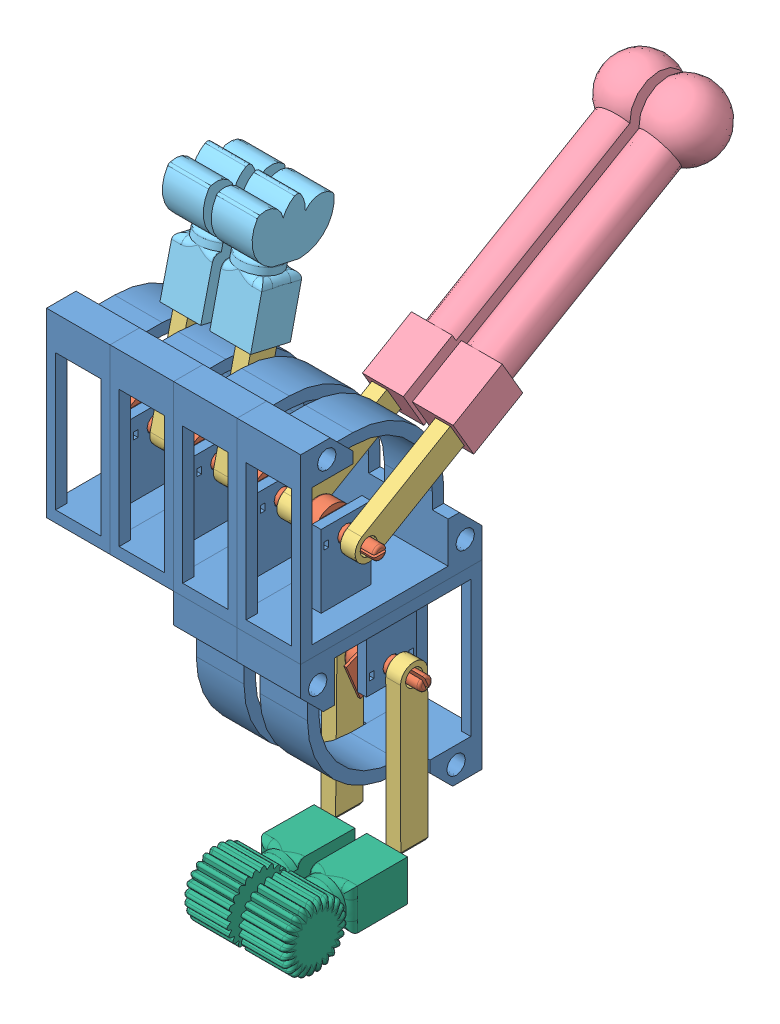
SolidWorks assembly throttle_quadrant_module_v3, configuration По умолчанию. Lengths in mm.
Overall size (120 253.77 210.33).
24 component instances, 6 part files, 57 mates.
Components (placement in the parent):
- throttle_quadrant_axis_module_throttle_quadrant01a-1: throttle_quadrant_axis_module_throttle_quadrant01a [По умолчанию] at origin size (28 80 80)
- 16K1-B10K-1: 16K1-B10K [По умолчанию] at (5.1 0 0) x (0 -1 0) z (0 0 1) size (20 28.16 16.3)
- throttle_quadrant_axis_module_slider_throttle_quadrant02a-1: throttle_quadrant_axis_module_slider_throttle_quadrant02a [По умолчанию] at (28 0 0) x (0 0.222506 0.974931) z (0 -0.974931 0.222506) size (12 6.5 71)
- throttle_quadrant_axis_module_throttle_quadrant01a-2: throttle_quadrant_axis_module_throttle_quadrant01a [По умолчанию] at (28 0 0) size (28 80 80)
- 16K1-B10K-2: 16K1-B10K [По умолчанию] at (33.1 0 0) x (0 -1 0) z (0 0 1) size (20 28.16 16.3)
- throttle_quadrant_axis_module_throttle_quadrant01a-4: throttle_quadrant_axis_module_throttle_quadrant01a [По умолчанию] at (56 0 0) size (28 80 80)
- throttle_quadrant_axis_module_slider_throttle_quadrant02a-2: throttle_quadrant_axis_module_slider_throttle_quadrant02a [По умолчанию] at (56 0 0) x (0 0.863825 0.503792) z (0 -0.503792 0.863825) size (12 6.5 71)
- throttle_quadrant_axis_module_slider_throttle_quadrant02a-3: throttle_quadrant_axis_module_slider_throttle_quadrant02a [По умолчанию] at (84 0 0) x (0 0.863572 0.504225) z (0 -0.504225 0.863572) size (12 6.5 71)
- 16K1-B10K-3: 16K1-B10K [По умолчанию] at (61.1 0 0) x (0 -1 0) z (0 0 1) size (20 28.16 16.3)
- mi8_throttle-1: mi8_throttle [По умолчанию] at (69 29.1657 -49.5546) x (1 0 0) z (0 0.863572 0.504225) size (23.51 140 30)
- mi8_throttle-2: mi8_throttle [По умолчанию] at (65 29.1408 -49.5692) x (-1 0 0) z (0 -0.863825 -0.503792) size (23.51 140 30)
- throttle_quadrant_axis_module_throttle_quadrant01a-5: throttle_quadrant_axis_module_throttle_quadrant01a [По умолчанию] at (-28 0 0) size (28 80 80)
- 16K1-B10K-4: 16K1-B10K [По умолчанию] at (-22.9 0 0) x (0 -1 0) z (0 0 1) size (20 28.16 16.3)
- throttle_quadrant_axis_module_slider_throttle_quadrant02a-4: throttle_quadrant_axis_module_slider_throttle_quadrant02a [По умолчанию] x (0 0.23184 0.972754) z (0 -0.972754 0.23184) size (12 6.5 71)
- prop_knob-1: prop_knob [По умолчанию] at (8.5 55.9797 -13.1363) x (-1 0 0) z (0 -0.23184 -0.972754) size (18 54.43 36.33)
- prop_knob-2: prop_knob [По умолчанию] at (12.5 56.0141 -12.9891) x (1 0 0) z (0 0.222506 0.974931) size (18 54.43 36.33)
- throttle_quadrant_axis_module_throttle_quadrant01a-6: throttle_quadrant_axis_module_throttle_quadrant01a [По умолчанию] at (28 -60 -20) x (1 0 0) z (0 0 -1) size (28 80 80)
- throttle_quadrant_axis_module_throttle_quadrant01a-7: throttle_quadrant_axis_module_throttle_quadrant01a [По умолчанию] at (56 -60 -20) x (1 0 0) z (0 0 -1) size (28 80 80)
- 16K1-B10K-5: 16K1-B10K [По умолчанию] at (33.1 -60 -20) x (0 -0.381849 0.924225) z (0 0.924225 0.381849) size (20 28.16 16.3)
- 16K1-B10K-6: 16K1-B10K [По умолчанию] at (61.1 -60 -20) x (0 -0.381849 0.924225) z (0 0.924225 0.381849) size (20 28.16 16.3)
- throttle_quadrant_axis_module_slider_throttle_quadrant02a-5: throttle_quadrant_axis_module_slider_throttle_quadrant02a [По умолчанию] at (56 -60 -20) x (0 -0.009491 -0.999955) z (0 0.999955 -0.009491) size (12 6.5 71)
- throttle_quadrant_axis_module_slider_throttle_quadrant02a-6: throttle_quadrant_axis_module_slider_throttle_quadrant02a [По умолчанию] at (84 -60 -20) x (0 0.001944 -0.999998) z (0 0.999998 0.001944) size (12 6.5 71)
- mix_knob-1: mix_knob [По умолчанию] at (64.5 -132.8211 -0.808) x (-1 0 0) z (0 0.999955 -0.009491) size (20 56.24 28.48)
- mix_knob-2: mix_knob [По умолчанию] at (69 -133.0358 -1.6419) x (1 0 0) z (0 -0.999998 -0.001944) size (20 56.24 28.48)
Mates (geometry in assembly coordinates):
- Concentric1: concentric anti-aligned: cylinder of throttle_quadrant_axis_module_throttle_quadrant01a-1 through (14 0 0) axis (1 0 0) radius 3.7; cylinder of 16K1-B10K-1 through (20.4 0 0) axis (-1 0 0) radius 3.35
- Coincident1: coincident anti-aligned: plane of throttle_quadrant_axis_module_throttle_quadrant01a-1 through (14 0 0) normal (-1 0 0); plane of 16K1-B10K-1 through (14 0 0) normal (1 0 0)
- Concentric2: concentric anti-aligned: cylinder of 16K1-B10K-1 through (33.2 0 0) axis (-1 0 0) radius 2.9; cylinder of throttle_quadrant_axis_module_slider_throttle_quadrant02a-1 through (21.5 0 0) axis (1 0 0) radius 3.75
- Distance2: distance = 0.5 mm anti-aligned: plane of throttle_quadrant_axis_module_slider_throttle_quadrant02a-1 through (21.5 0 0) normal (-1 0 0); plane of throttle_quadrant_axis_module_throttle_quadrant01a-1 through (21 0 0) normal (1 0 0)
- Concentric3: concentric aligned: cylinder of throttle_quadrant_axis_module_throttle_quadrant01a-1 through (0 42.5 18.5) axis (1 0 0) radius 4.1; cylinder of throttle_quadrant_axis_module_throttle_quadrant01a-2 through (28 42.5 18.5) axis (1 0 0) radius 4.1
- Concentric4: concentric aligned: cylinder of throttle_quadrant_axis_module_throttle_quadrant01a-1 through (0 -18.5 -42.5) axis (1 0 0) radius 4.1; cylinder of throttle_quadrant_axis_module_throttle_quadrant01a-2 through (28 -18.5 -42.5) axis (1 0 0) radius 4.1
- Coincident5: coincident anti-aligned: plane of throttle_quadrant_axis_module_throttle_quadrant01a-1 through (28 0 0) normal (1 0 0); plane of throttle_quadrant_axis_module_throttle_quadrant01a-2 through (28 0 0) normal (-1 0 0)
- Concentric5: concentric anti-aligned: cylinder of throttle_quadrant_axis_module_throttle_quadrant01a-2 through (42 0 0) axis (1 0 0) radius 3.7; cylinder of 16K1-B10K-2 through (48.4 0 0) axis (-1 0 0) radius 3.35
- Coincident6: coincident anti-aligned: plane of throttle_quadrant_axis_module_throttle_quadrant01a-2 through (42 0 0) normal (-1 0 0); plane of 16K1-B10K-2 through (42 0 0) normal (1 0 0)
- Concentric8: concentric aligned: cylinder of throttle_quadrant_axis_module_throttle_quadrant01a-2 through (28 42.5 18.5) axis (1 0 0) radius 4.1; cylinder of throttle_quadrant_axis_module_throttle_quadrant01a-4 through (56 42.5 18.5) axis (1 0 0) radius 4.1
- Concentric9: concentric aligned: cylinder of throttle_quadrant_axis_module_throttle_quadrant01a-2 through (28 -18.5 -42.5) axis (1 0 0) radius 4.1; cylinder of throttle_quadrant_axis_module_throttle_quadrant01a-4 through (56 -18.5 -42.5) axis (1 0 0) radius 4.1
- Coincident8: coincident anti-aligned: plane of throttle_quadrant_axis_module_throttle_quadrant01a-2 through (56 0 0) normal (1 0 0); plane of throttle_quadrant_axis_module_throttle_quadrant01a-4 through (56 0 0) normal (-1 0 0)
- Concentric10: concentric anti-aligned: cylinder of 16K1-B10K-2 through (61.2 0 0) axis (-1 0 0) radius 2.9; cylinder of throttle_quadrant_axis_module_slider_throttle_quadrant02a-2 through (49.5 0 0) axis (1 0 0) radius 3.75
- Concentric11: concentric anti-aligned: cylinder of throttle_quadrant_axis_module_throttle_quadrant01a-4 through (70 0 0) axis (1 0 0) radius 3.7; cylinder of 16K1-B10K-3 through (76.4 0 0) axis (-1 0 0) radius 3.35
- Coincident10: coincident anti-aligned: plane of throttle_quadrant_axis_module_throttle_quadrant01a-4 through (70 0 0) normal (-1 0 0); plane of 16K1-B10K-3 through (70 0 0) normal (1 0 0)
- Concentric12: concentric anti-aligned: cylinder of throttle_quadrant_axis_module_slider_throttle_quadrant02a-3 through (77.5 0 0) axis (1 0 0) radius 3.75; cylinder of 16K1-B10K-3 through (89.2 0 0) axis (-1 0 0) radius 2.9
- Distance4: distance = 0.5 mm anti-aligned: plane of throttle_quadrant_axis_module_slider_throttle_quadrant02a-2 through (49.5 0 0) normal (-1 0 0); plane of throttle_quadrant_axis_module_throttle_quadrant01a-2 through (49 0 0) normal (1 0 0)
- Distance5: distance = 0.5 mm anti-aligned: plane of throttle_quadrant_axis_module_slider_throttle_quadrant02a-3 through (77.5 0 0) normal (-1 0 0); plane of throttle_quadrant_axis_module_throttle_quadrant01a-4 through (77 0 0) normal (1 0 0)
- Coincident13: coincident anti-aligned: plane of throttle_quadrant_axis_module_slider_throttle_quadrant02a-3 through (77.5 0 0) normal (-1 0 0); plane of mi8_throttle-1 through (77.5 27.5932 -59.1575) normal (1 0 0)
- Coincident14: coincident anti-aligned: plane of throttle_quadrant_axis_module_slider_throttle_quadrant02a-3 through (77.5 27.5932 -59.1575) normal (0 0.504225 -0.863572); plane of mi8_throttle-1 through (69 32.9474 -56.0313) normal (0 -0.504225 0.863572)
- Coincident15: coincident anti-aligned: plane of throttle_quadrant_axis_module_slider_throttle_quadrant02a-3 through (77.5 -5.1814 -3.0254) normal (0 -0.863572 -0.504225); plane of mi8_throttle-1 through (77.5 27.5932 -59.1575) normal (0 0.863572 0.504225)
- Coincident16: coincident anti-aligned: plane of throttle_quadrant_axis_module_slider_throttle_quadrant02a-2 through (49.5 0 0) normal (-1 0 0); plane of mi8_throttle-2 through (49.5 38.275 -52.9243) normal (1 0 0)
- Coincident17: coincident anti-aligned: plane of throttle_quadrant_axis_module_slider_throttle_quadrant02a-2 through (49.5 27.5636 -59.1714) normal (0 0.503792 -0.863825); plane of mi8_throttle-2 through (65 32.9193 -56.0479) normal (0 -0.503792 0.863825)
- Coincident18: coincident anti-aligned: plane of throttle_quadrant_axis_module_slider_throttle_quadrant02a-2 through (49.5 -5.1829 -3.0228) normal (0 -0.863825 -0.503792); plane of mi8_throttle-2 through (56.5 27.5636 -59.1714) normal (0 0.863825 0.503792)
- Concentric14: concentric aligned: cylinder of throttle_quadrant_axis_module_throttle_quadrant01a-1 through (0 42.5 18.5) axis (1 0 0) radius 4.1; cylinder of throttle_quadrant_axis_module_throttle_quadrant01a-5 through (-28 42.5 18.5) axis (1 0 0) radius 4.1
- Concentric15: concentric aligned: cylinder of throttle_quadrant_axis_module_throttle_quadrant01a-1 through (0 -18.5 -42.5) axis (1 0 0) radius 4.1; cylinder of throttle_quadrant_axis_module_throttle_quadrant01a-5 through (-28 -18.5 -42.5) axis (1 0 0) radius 4.1
- Coincident19: coincident anti-aligned: plane of throttle_quadrant_axis_module_throttle_quadrant01a-1 through (0 0 0) normal (-1 0 0); plane of throttle_quadrant_axis_module_throttle_quadrant01a-5 through (0 0 0) normal (1 0 0)
- Concentric16: concentric anti-aligned: cylinder of throttle_quadrant_axis_module_throttle_quadrant01a-5 through (-14 0 0) axis (1 0 0) radius 3.7; cylinder of 16K1-B10K-4 through (-7.6 0 0) axis (-1 0 0) radius 3.35
- Coincident20: coincident anti-aligned: plane of throttle_quadrant_axis_module_throttle_quadrant01a-5 through (-14 0 0) normal (-1 0 0); plane of 16K1-B10K-4 through (-14 0 0) normal (1 0 0)
- Concentric17: concentric anti-aligned: cylinder of 16K1-B10K-4 through (5.2 0 0) axis (-1 0 0) radius 2.9; cylinder of throttle_quadrant_axis_module_slider_throttle_quadrant02a-4 through (-6.5 0 0) axis (1 0 0) radius 3.75
- Distance6: distance = 0.5 mm anti-aligned: plane of throttle_quadrant_axis_module_slider_throttle_quadrant02a-4 through (-6.5 0 0) normal (-1 0 0); plane of throttle_quadrant_axis_module_throttle_quadrant01a-5 through (-7 0 0) normal (1 0 0)
- Coincident22: coincident anti-aligned: plane of throttle_quadrant_axis_module_slider_throttle_quadrant02a-1; plane of prop_knob-2
- Coincident23: coincident anti-aligned: plane of throttle_quadrant_axis_module_slider_throttle_quadrant02a-1; plane of prop_knob-2
- Coincident24: coincident anti-aligned: plane of throttle_quadrant_axis_module_slider_throttle_quadrant02a-1 through (28 0 0) normal (1 0 0); plane of prop_knob-2 through (28 61.9465 -20.7024) normal (-1 0 0)
- Coincident25: coincident anti-aligned: plane of throttle_quadrant_axis_module_slider_throttle_quadrant02a-4 through (-6.5 61.838 -20.9061) normal (0 0.972754 -0.23184); plane of prop_knob-1 through (8.5 63.2754 -14.8751) normal (0 -0.972754 0.23184)
- Coincident32: coincident anti-aligned: plane of throttle_quadrant_axis_module_slider_throttle_quadrant02a-4 through (0 0 0) normal (1 0 0); plane of prop_knob-1 through (0 64.7128 -8.844) normal (-1 0 0)
- Coincident33: coincident anti-aligned: plane of throttle_quadrant_axis_module_slider_throttle_quadrant02a-4 through (-6.5 -1.391 -5.8365) normal (0 -0.23184 -0.972754); plane of prop_knob-1 through (0 61.838 -20.9061) normal (0 0.23184 0.972754)
- Coincident38: coincident anti-aligned: plane of throttle_quadrant_axis_module_throttle_quadrant01a-6 through (56 -60 -20) normal (1 0 0); plane of throttle_quadrant_axis_module_throttle_quadrant01a-7 through (56 -60 -20) normal (-1 0 0)
- Concentric18: concentric aligned: cylinder of throttle_quadrant_axis_module_throttle_quadrant01a-6 through (28 -102.5 -38.5) axis (1 0 0) radius 4.1; cylinder of throttle_quadrant_axis_module_throttle_quadrant01a-7 through (56 -102.5 -38.5) axis (1 0 0) radius 4.1
- Concentric20: concentric anti-aligned: cylinder of throttle_quadrant_axis_module_throttle_quadrant01a-7 through (70 -60 -20) axis (1 0 0) radius 3.7; cylinder of 16K1-B10K-6 through (76.4 -60 -20) axis (-1 0 0) radius 3.35
- Coincident39: coincident anti-aligned: plane of throttle_quadrant_axis_module_throttle_quadrant01a-7 through (70 -60 -20) normal (-1 0 0); plane of 16K1-B10K-6 through (70 -60 -20) normal (1 0 0)
- Concentric21: concentric anti-aligned: cylinder of throttle_quadrant_axis_module_throttle_quadrant01a-6 through (42 -60 -20) axis (1 0 0) radius 3.7; cylinder of 16K1-B10K-5 through (48.4 -60 -20) axis (-1 0 0) radius 3.35
- Coincident40: coincident anti-aligned: plane of throttle_quadrant_axis_module_throttle_quadrant01a-6 through (42 -60 -20) normal (-1 0 0); plane of 16K1-B10K-5 through (42 -60 -20) normal (1 0 0)
- Concentric22: concentric anti-aligned: cylinder of 16K1-B10K-6 through (89.2 -60 -20) axis (-1 0 0) radius 2.9; cylinder of throttle_quadrant_axis_module_slider_throttle_quadrant02a-6 through (77.5 -60 -20) axis (1 0 0) radius 3.75
- Distance7: distance = 0.5 mm anti-aligned: plane of throttle_quadrant_axis_module_slider_throttle_quadrant02a-6 through (77.5 -60 -20) normal (-1 0 0); plane of throttle_quadrant_axis_module_throttle_quadrant01a-7 through (77 -60 -20) normal (1 0 0)
- Concentric23: concentric anti-aligned: cylinder of 16K1-B10K-5 through (61.2 -60 -20) axis (-1 0 0) radius 2.9; cylinder of throttle_quadrant_axis_module_slider_throttle_quadrant02a-5 through (49.5 -60 -20) axis (1 0 0) radius 3.75
- Distance8: distance = 0.5 mm anti-aligned: plane of throttle_quadrant_axis_module_slider_throttle_quadrant02a-5 through (49.5 -60 -20) normal (-1 0 0); plane of throttle_quadrant_axis_module_throttle_quadrant01a-6 through (49 -60 -20) normal (1 0 0)
- Concentric29: concentric aligned: cylinder of throttle_quadrant_axis_module_throttle_quadrant01a-6 through (28 -41.5 22.5) axis (1 0 0) radius 4.1; cylinder of throttle_quadrant_axis_module_throttle_quadrant01a-7 through (56 -41.5 22.5) axis (1 0 0) radius 4.1
- Coincident54: coincident anti-aligned: plane of throttle_quadrant_axis_module_throttle_quadrant01a-2 through (56 -30 -40) normal (0 -1 0); plane of throttle_quadrant_axis_module_throttle_quadrant01a-7 through (84 -30 20) normal (0 1 0)
- Coincident55: coincident anti-aligned: line of throttle_quadrant_axis_module_throttle_quadrant01a-4 through (84 -30 30) axis (-1 0 0); line of throttle_quadrant_axis_module_throttle_quadrant01a-7 through (56 -30 30) axis (1 0 0)
- Coincident56: coincident aligned: plane of throttle_quadrant_axis_module_throttle_quadrant01a-4 through (84 0 0) normal (1 0 0); plane of throttle_quadrant_axis_module_throttle_quadrant01a-7 through (84 -60 -20) normal (1 0 0)
- Coincident57: coincident aligned: line of throttle_quadrant_axis_module_slider_throttle_quadrant02a-5 through (49.5 -123.9402 -13.3928) axis (1 0 0); line of mix_knob-1 through (46.5 -123.9402 -13.3928) axis (1 0 0)
- Coincident58: coincident anti-aligned: plane of throttle_quadrant_axis_module_slider_throttle_quadrant02a-5 through (49.5 -59.9431 -14.0003) normal (0 0.009491 0.999955); plane of mix_knob-1 through (46.5 -141.9394 -13.222) normal (0 -0.009491 -0.999955)
- Coincident60: coincident anti-aligned: plane of throttle_quadrant_axis_module_slider_throttle_quadrant02a-5 through (56 -60 -20) normal (1 0 0); plane of mix_knob-1 through (56 -138.9497 6.7505) normal (-1 0 0)
- Coincident61: coincident: plane of throttle_quadrant_axis_module_slider_throttle_quadrant02a-6 through (77.5 -60.0117 -14) normal (0 -0.001944 0.999998); plane of mix_knob-2 through (87 -152.9467 -14.1807) normal (0 0.001944 -0.999998)
- Coincident62: coincident: plane of throttle_quadrant_axis_module_slider_throttle_quadrant02a-6 through (77.5 -60 -20) normal (-1 0 0); plane of mix_knob-2 through (77.5 -155.7856 5.8139) normal (1 0 0)
- Coincident63: coincident anti-aligned: line of throttle_quadrant_axis_module_slider_throttle_quadrant02a-6 through (77.5 -124.0115 -14.1244) axis (1 0 0); line of mix_knob-2 through (87 -124.0115 -14.1244) axis (-1 0 0)
